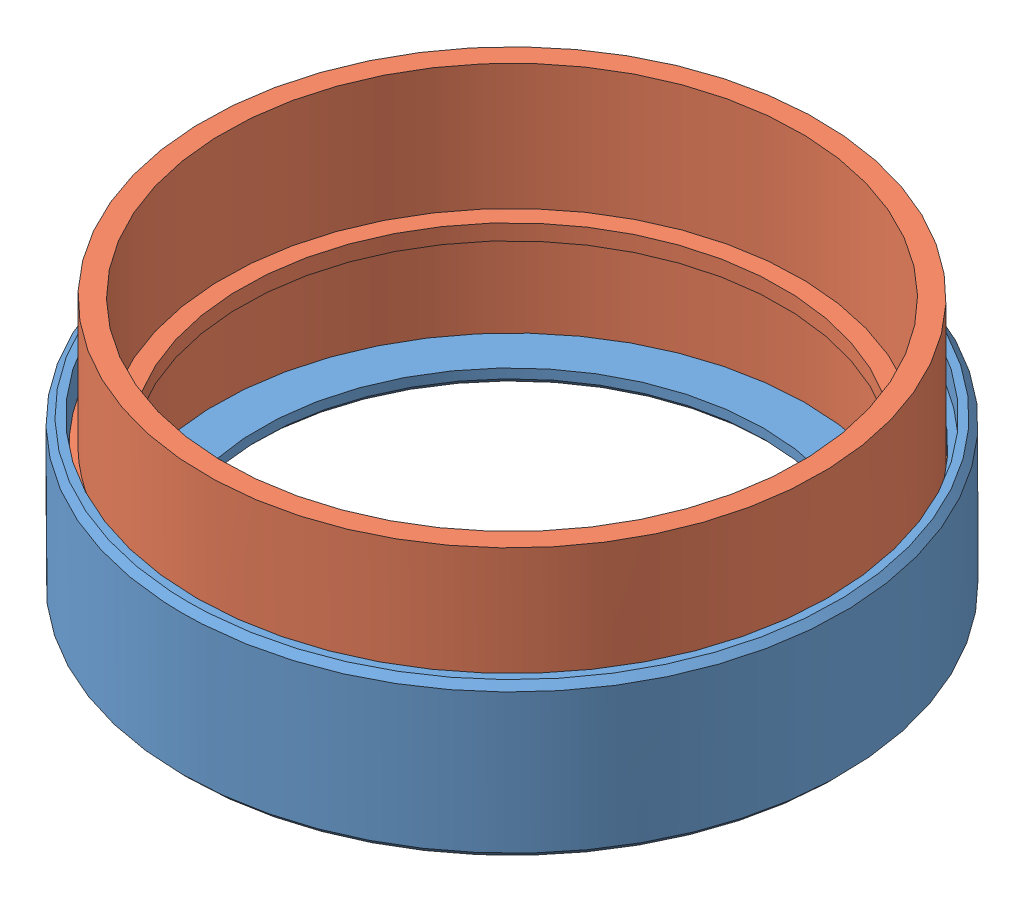
SolidWorks assembly motor_retainer, configuration Default. Lengths in mm.
Overall size (68.51 25.72 68.51).
2 component instances, 2 part files, 2 mates.
Components (placement in the parent):
- retainer_cap-1: retainer_cap [Default] at (19.0719 27.9343 53.5211) size (66.55 15.37 66.55)
- retainer_body-1: retainer_body [Default] at (19.0719 53.6518 53.5211) x (-0.086968 0 0.996211) z (0.996211 0 0.086968) size (63.25 24.13 63.25)
Mates (geometry in assembly coordinates):
- Coincident1: coincident anti-aligned: plane of RA54-Knurled-1 through (44.4719 29.5218 53.5211) normal (0 1 0); plane of RA54P-TW-Base-1 through (16.377 29.5218 84.3917) normal (0 -1 0)
- Concentric1: concentric anti-aligned: cylinder of RA54-Knurled-1 through (19.0719 27.9343 53.5211) axis (0 -1 0) radius 31.877; cylinder of RA54P-TW-Base-1 through (19.0719 53.6518 53.5211) axis (0 1 0) radius 30.988
